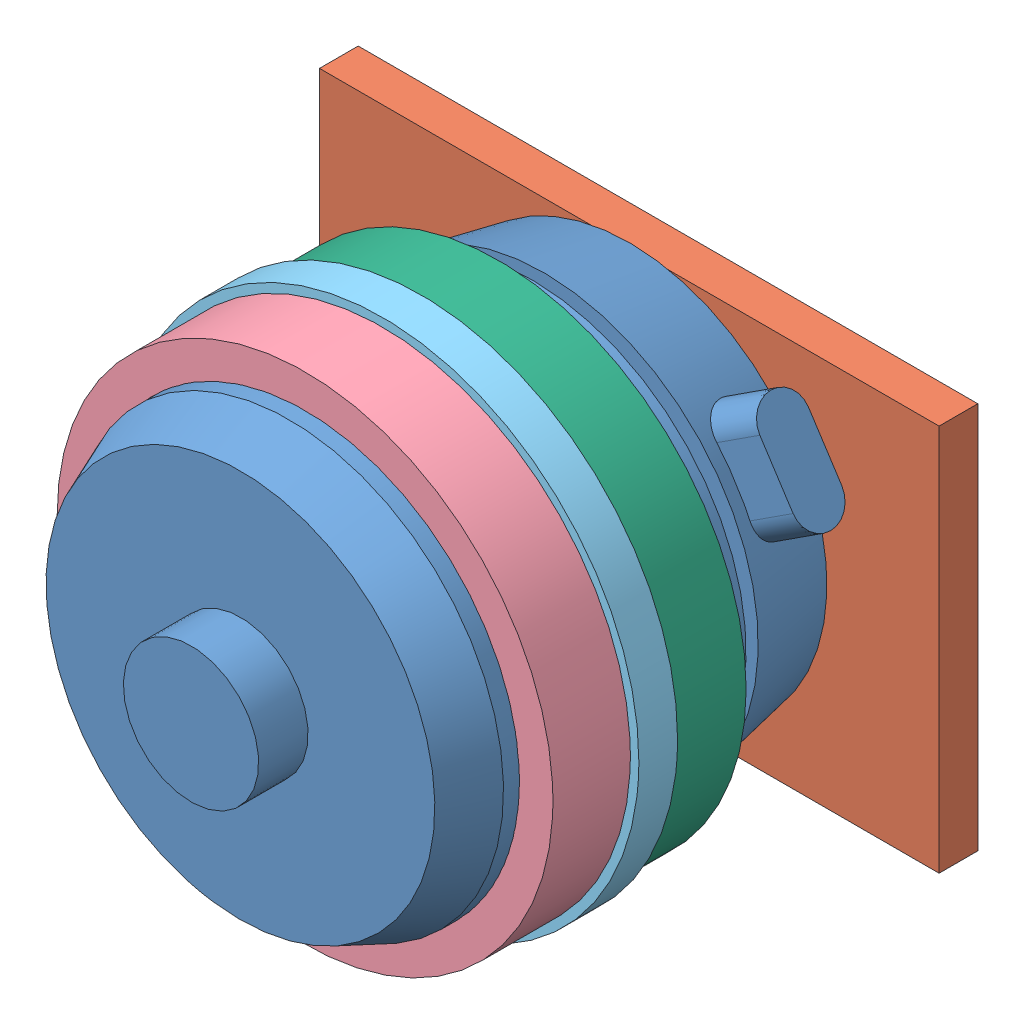
SolidWorks assembly motor_assm, configuration Default. Lengths in mm.
Overall size (47.71 44.61 39.22).
9 component instances, 6 part files, 17 mates.
Components (placement in the parent):
- motor-1: motor [Default] at (-6.8199 1.7338 20.3787) x (-0.207912 -0.978148 0) z (0 0 1) size (35.88 35.88 37.48)
- motor_mount-1: motor_mount [Default] at (-6.8199 1.7338 -18.7276) size (47.65 31.32 3.17)
- m3-8-1: m3-8 [91294A128] at (-4.2065 14.0291 -10.7276) size (6 6 8.55)
- m3-8-2: m3-8 [91294A128] at (-16.1563 3.7183 -10.7276) x (0.997405 -0.071995 0) z (0 0 1) size (6 6 8.55)
- m3-8-3: m3-8 [91294A128] at (-9.4334 -10.5615 -10.7276) size (6 6 8.55)
- m3-8-4: m3-8 [91294A128] at (2.5165 -0.2507 -10.7276) size (6 6 8.55)
- hub-2: hub [Default] at (-6.8199 1.7338 4.681) x (0 0 1) z (-0.999994 -0.003324 0) size (6.35 40.65 40.65)
- tire_timing_belt-1: tire_timing_belt [Default] at (-6.8199 1.7338 1.506) x (0 0 1) z (-0.998008 0.063081 0) size (3.17 42.04 42.04)
- hub_aluminum-1: hub_aluminum [Default] at (-6.8199 1.7338 4.681) x (0.999999 -0.001411 0) z (0 0 1) size (40.59 40.59 9.53)
Mates (geometry in assembly coordinates):
- Coincident3: coincident anti-aligned: plane of motor-1 through (9.031 -1.6354 -15.5526) normal (0 0 -1); plane of motor_mount-1 through (18.5801 17.3929 -15.5526) normal (0 0 1)
- Concentric2: concentric anti-aligned: cylinder of motor-1 through (-6.8199 1.7338 1020.3787) axis (0 0 1) radius 4.7307; cylinder of motor_mount-1 through (-6.8199 1.7338 -15.5526) axis (0 0 -1) radius 5.461
- Parallel1: parallel aligned: plane of motor_mount-1 through (-29.0703 17.3929 -15.5526) normal (0 1 0); plane of assembly through (0 0 0) normal (0 1 0)
- Concentric3: concentric aligned: cylinder of motor-1 through (2.5165 -0.2507 -8.5526) axis (0 0 -1) radius 1.29; cylinder of motor_mount-1 through (2.5165 -0.2507 -15.5526) axis (0 0 -1) radius 1.7
- Coincident4: coincident: plane of motor_mount-1 through (18.5801 17.3929 -18.7276) normal (0 0 -1); line of m3-8-1 through (-4.2065 15.1838 -18.7276) axis (-0.866025 -0.5 0)
- Coincident5: coincident aligned: plane of motor_mount-1 through (18.5801 17.3929 -18.7276) normal (0 0 -1); plane of m3-8-4 through (2.5165 -0.2507 -18.7276) normal (0 0 -1)
- Coincident6: coincident aligned: plane of motor_mount-1 through (18.5801 17.3929 -18.7276) normal (0 0 -1); circle of m3-8-3
- Coincident7: coincident aligned: plane of motor_mount-1 through (18.5801 17.3929 -18.7276) normal (0 0 -1); circle of m3-8-2
- Coincident8: coincident anti-aligned: circle of motor_mount-1; circle of m3-8-4
- Coincident9: coincident anti-aligned: circle of motor_mount-1; circle of m3-8-1
- Coincident10: coincident anti-aligned: circle of motor_mount-1; circle of m3-8-3
- Coincident11: coincident anti-aligned: circle of motor_mount-1; circle of m3-8-2
- Concentric7: concentric anti-aligned: cylinder of motor-1 through (-6.8199 1.7338 1020.3787) axis (0 0 1) radius 17.575; cylinder of hub-2 through (-6.8199 1.7338 11.031) axis (0 0 -1) radius 17.575
- Concentric8: concentric anti-aligned: cylinder of motor-1 through (-6.8199 1.7338 1020.3787) axis (0 0 1) radius 17.575; cylinder of tire_timing_belt-1 through (-6.8199 1.7338 4.681) axis (0 0 -1) radius 19.4337
- Concentric9: concentric aligned: cylinder of motor-1 through (-6.8199 1.7338 1020.3787) axis (0 0 1) radius 17.575; cylinder of hub_aluminum-1 through (-6.8199 1.7338 1004.681) axis (0 0 1) radius 17.5
- Coincident12: coincident anti-aligned: plane of hub-2 through (-6.8199 1.7338 4.681) normal (0 0 -1); plane of hub_aluminum-1 through (-6.7925 21.1675 4.681) normal (0 0 1)
- Coincident13: coincident anti-aligned: plane of tire_timing_belt-1 through (-6.8199 1.7338 1.506) normal (0 0 -1); plane of hub_aluminum-1 through (-6.7913 22.0278 1.506) normal (0 0 1)
